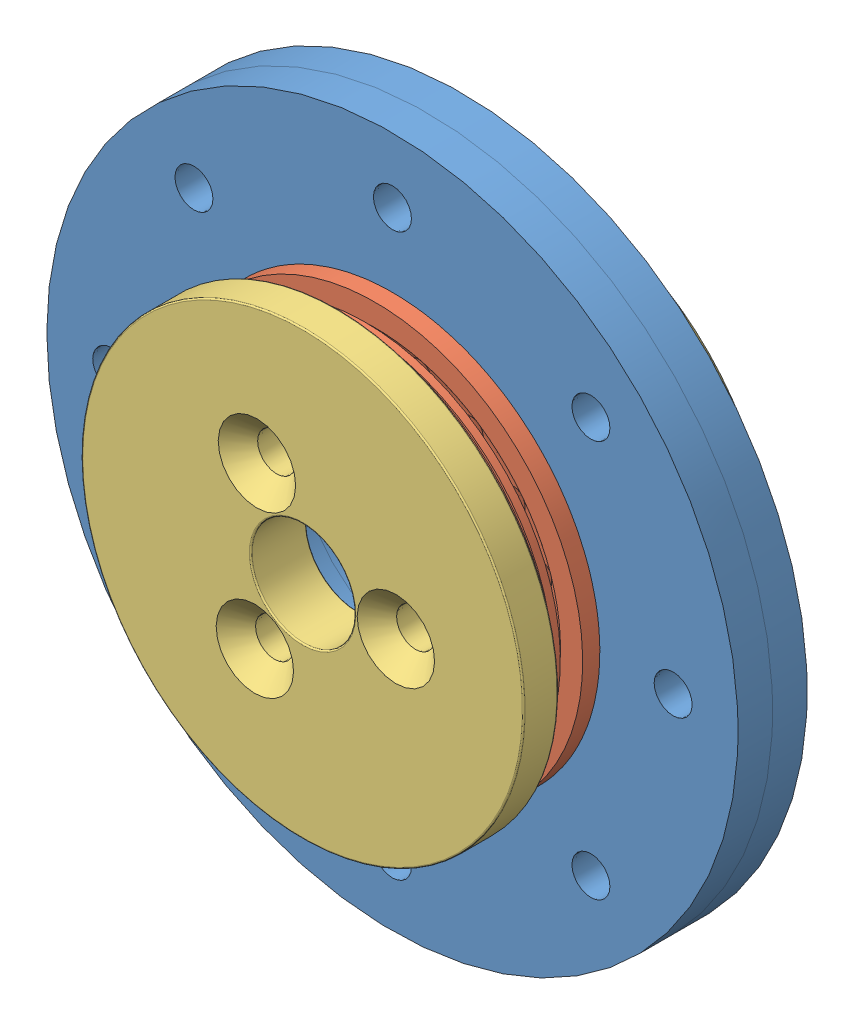
SolidWorks assembly Ensamblaje1, configuration Predeterminado. Lengths in mm.
Overall size (100 100 36).
6 component instances, 3 part files, 11 mates.
Components (placement in the parent):
- 4_Apoya rod rev2-1: 4_Apoya rod rev2 [Predeterminado] at (-2.0174 -4.7409 95) size (100 100 5)
- single direction thrust ball bearing_ks-1: single direction thrust ball bearing_ks [KS B 2022 ST - 51108-D] at (-2.0174 -4.7409 104.5) x (0.912212 -0.409718 0) z (0 0 -1) size (60 60 13)
- 3_sujeta_rod_sup rev2-1: 3_sujeta_rod_sup rev2 [Predeterminado] at (-2.0174 -4.7409 113) x (0.859555 -0.511044 0) z (0 0 -1) size (64 64 8)
- 4_Apoya rod rev2-2: 4_Apoya rod rev2 [Predeterminado] at (-2.0174 -4.7409 95) x (1 0 0) z (0 0 -1) size (100 100 5)
- single direction thrust ball bearing_ks-2: single direction thrust ball bearing_ks [KS B 2022 ST - 51108-D] at (-2.0174 -4.7409 85.5) x (0.272532 0.962147 0) z (0 0 1) size (60 60 13)
- 3_sujeta_rod_sup rev2-2: 3_sujeta_rod_sup rev2 [Predeterminado] at (-2.0174 -4.7409 77) x (-0.84325 -0.537521 0) z (0 0 1) size (64 64 8)
Mates (geometry in assembly coordinates):
- Concéntrica31: concentric anti-aligned: circle of 4_Apoya rod rev2-1; circle of single direction thrust ball bearing_ks-1
- Coincidente51: coincident anti-aligned: plane of 4_Apoya rod rev2-1 through (-2.0174 -4.7409 98) normal (0 0 1); plane of single direction thrust ball bearing_ks-1 through (-14.3089 -32.1073 98) normal (0 0 -1)
- Concéntrica61: concentric anti-aligned: cylinder of 4_Apoya rod rev2-1 through (-2.0174 -4.7409 100) axis (0 0 -1) radius 19; cylinder of 3_sujeta_rod_sup rev2-1 through (-2.0174 -4.7409 108) axis (0 0 1) radius 7.5
- Coincidente71: coincident anti-aligned: plane of single direction thrust ball bearing_ks-1 through (-14.3089 -32.1073 111) normal (0 0 1); plane of 3_sujeta_rod_sup rev2-1 through (-2.0174 -4.7409 111) normal (0 0 -1)
- Concéntrica81: concentric anti-aligned: circle of 4_Apoya rod rev2-1; circle of 4_Apoya rod rev2-2
- Concéntrica91: concentric anti-aligned: cylinder of 4_Apoya rod rev2-1 through (-42.6204 -4.7409 87.2218) axis (0 0 1) radius 2.75; cylinder of 4_Apoya rod rev2-2 through (-42.6204 -4.7409 102.7782) axis (0 0 -1) radius 2.75
- Coincidente91: coincident anti-aligned: plane of 4_Apoya rod rev2-1 through (-2.0174 -4.7409 95) normal (0 0 -1); plane of 4_Apoya rod rev2-2 through (-2.0174 -4.7409 95) normal (0 0 1)
- Concéntrica101: concentric anti-aligned: circle of 4_Apoya rod rev2-2; circle of single direction thrust ball bearing_ks-2
- Coincidente101: coincident anti-aligned: plane of 4_Apoya rod rev2-2 through (-2.0174 -4.7409 92) normal (0 0 -1); plane of single direction thrust ball bearing_ks-2 through (-30.8818 3.4351 92) normal (0 0 1)
- Concéntrica111: concentric anti-aligned: cylinder of single direction thrust ball bearing_ks-2 through (-2.0174 -4.7409 104.459) axis (0 0 1) radius 20; cylinder of 3_sujeta_rod_sup rev2-2 through (-2.0174 -4.7409 82) axis (0 0 -1) radius 7.5
- Coincidente111: coincident anti-aligned: plane of single direction thrust ball bearing_ks-2 through (-30.8818 3.4351 79) normal (0 0 -1); plane of 3_sujeta_rod_sup rev2-2 through (-2.0174 -4.7409 79) normal (0 0 1)
